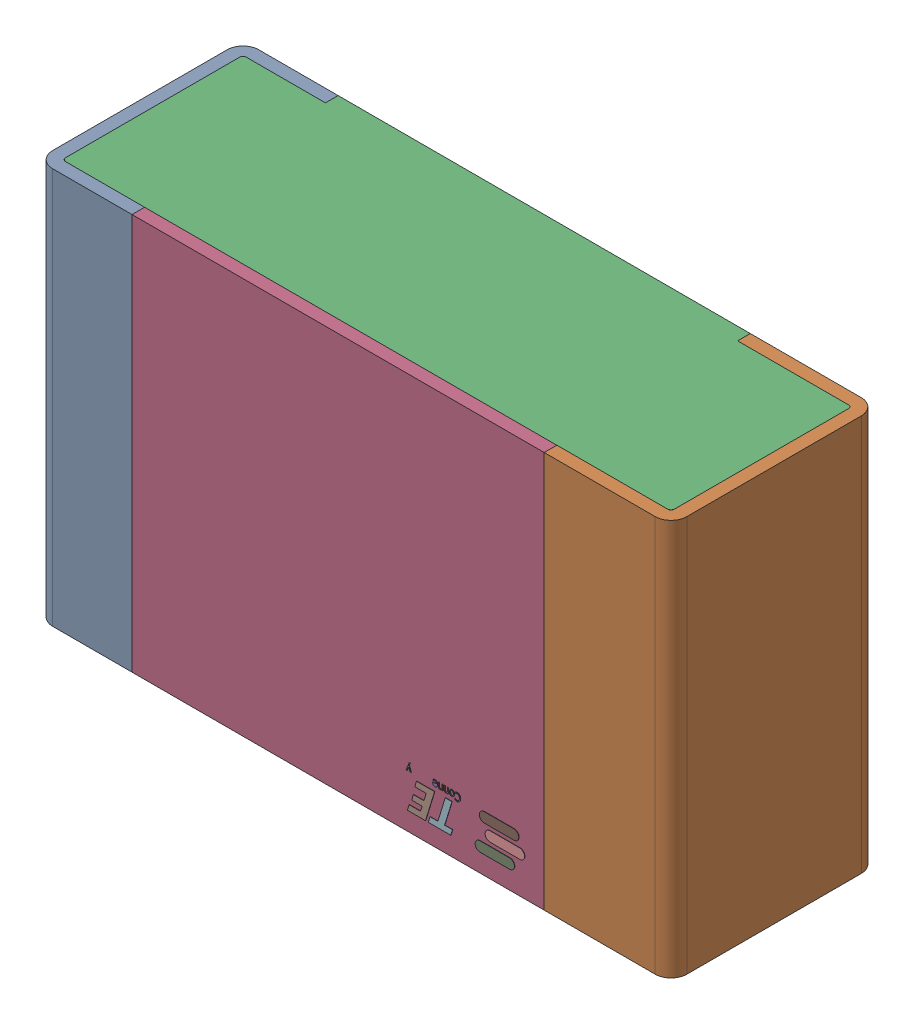
SolidWorks assembly RLL5.step, configuration Default. Lengths in mm.
Overall size (2 1.25 0.65).
5 component instances, 4 part files, 0 mates.
Components (placement in the parent):
- Res_TE_Connectivity_CPF0805B66R5E1_eec.step-1: Res_TE_Connectivity_CPF0805B66R5E1_eec.step [Default] at (10.287 3.368 0) x (-1 0 0) z (0 0 1) size (2 1.25 0.65)
  - 1.step-1: 1.step [Default] at origin size (2 1.25 0.65)
  - 2.step-1: 2.step [Default] at origin size (1.92 1.25 0.61)
  - 3.step-1: 3.step [Default] at origin size (1.3 1.25 0.04)
  - TE connectivity Logo 1 (2).step-1: TE connectivity Logo 1 (2).step [Default] at (5.4285 0.313 0.551) x (-1 0 0) z (0 0 1) size (0.37 0.13 0.11)
